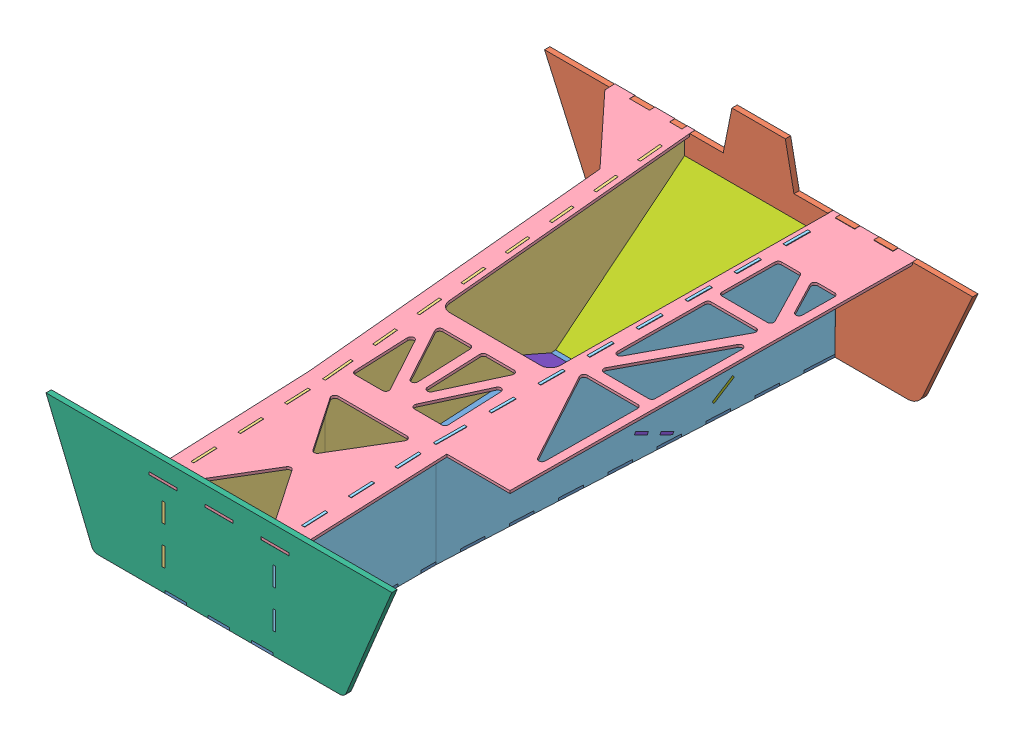
SolidWorks assembly Interior Frame Assembly, configuration Default. Lengths in mm.
Overall size (1628.61 625.54 2073.49).
8 component instances, 8 part files, 25 mates.
Components (placement in the parent):
- Roll Cage Floor Panel-1: Roll Cage Floor Panel [Default] at (605.2647 1125.8511 1278.9155) x (1 0 0) z (0 -1 0) size (582.08 2072.64 10.16)
- Rear Bulkhead-1: Rear Bulkhead [Default] at (-855.024 -1455.0318 1278.9155) size (1628.61 625.54 21.09)
- Side Wall Right-1: Side Wall Right [Default] at (605.2647 1125.8511 1278.9155) x (-1 0 0) z (0 1 0) size (85.33 2072.64 456.87)
- Top Cover-1: Top Cover [Default] at (554.794 1565.6751 1298.1949) x (-0.999997 -0.002279 -0.0001) z (-0.002281 0.999038 0.043792) size (1151.82 2074.69 15.42)
- MirrorSide Wall Right-4: MirrorSide Wall Right [Default] at (605.2647 1125.8511 1278.9155) x (1 0 0) z (0 -1 0) size (85.33 2072.64 456.87)
- Front Bulkhead^Interior Frame Assembly-1: Front Bulkhead^Interior Frame Assembly [Default] at (605.2647 1125.8511 3331.2355) size (1315.72 434.36 20.32) (virtual)
- Part6-1: Part6 [Default] at (605.2647 0 0) x (0 0 -1) z (1 0 0) size (517.46 368.06 582.08)
- Part7^Interior Frame Assembly-1: Part7^Interior Frame Assembly [Default] at (605.2647 0 0) x (0 0 -1) z (1 0 0) size (234.48 107.38 521.41) (virtual)
Mates (geometry in assembly coordinates):
- Coincident1: coincident anti-aligned: plane of Roll Cage Floor Panel-1 through (605.2647 1125.8511 1278.9155) normal (0 1 0); plane of Rear Bulkhead-1 through (-855.024 1125.8511 1273.8355) normal (0 -1 0)
- Coincident2: coincident aligned: plane of Roll Cage Floor Panel-1 through (605.2647 1115.6911 1278.9155) normal (0 0 -1); plane of Rear Bulkhead-1 through (-855.024 -1455.0318 1278.9155) normal (0 0 -1)
- InPlace1: in place: plane of ? through (605.2647 1125.8511 1278.9155) normal (0 1 0); plane of ? through (0 1125.8511 0) normal (0 1 0); moOrthogonalPlaneRef_w of ? through (605.2647 1125.8511 1278.9155) normal (0 1 0); plane of ? through (0 1125.8511 0) normal (0 0 -1); plane of ? through (605.2647 1125.8511 1278.9155) normal (0 1 0); plane of ? through (0 1125.8511 0) normal (1 0 0); plane of ? through (605.2647 1125.8511 1278.9155) normal (0 1 0); unknown of Side Wall Right-1
- Coincident7: coincident aligned: plane of Roll Cage Floor Panel-1; plane of Side Wall Right-1
- Coincident8: coincident aligned: moOrthogonalPlaneRef_w of Roll Cage Floor Panel-1 through (605.2647 1125.8511 1278.9155) normal (0 0 1); plane of Side Wall Right-1 through (605.2647 1125.8511 1278.9155) normal (0 0 1)
- Coincident9: coincident anti-aligned: moOrthogonalPlaneRef_w of Roll Cage Floor Panel-1 through (605.2647 1125.8511 1278.9155) normal (1 0 0); plane of Side Wall Right-1 through (605.2647 1125.8511 1278.9155) normal (-1 0 0)
- Parallel2: parallel aligned: plane of Roll Cage Floor Panel-1 through (605.2647 1125.8511 1278.9155) normal (1 0 0); plane of Wheel Bay Former-1 through (389.3829 1102.9911 2754.6555) normal (1 0 0)
- Coincident24: coincident anti-aligned: line of Side Wall Right-1 through (389.3829 1502.998 2741.9555) axis (0 -1 0); line of Wheel Bay Former-1 through (389.3829 1102.9911 2741.9555) axis (0 1 0)
- Distance2: distance = 12.7 mm: point of Side Wall Right-1; point of Wheel Bay Former-1
- InPlace2: in place: plane of ? through (605.2647 1115.6911 3331.2355) normal (0 0 1); plane of ? through (0 0 3331.2355) normal (0 0 1); plane of ? through (605.2647 1115.6911 3331.2355) normal (0 0 1); plane of ? through (0 0 3331.2355) normal (0 1 0); plane of ? through (605.2647 1115.6911 3331.2355) normal (0 0 1); plane of ? through (0 0 3331.2355) normal (1 0 0); plane of ? through (605.2647 1115.6911 3331.2355) normal (0 0 1); unknown of Front Bulkhead^Interior Frame Assembly-1
- Coincident25: coincident aligned: plane of Roll Cage Floor Panel-1; plane of Front Bulkhead^Interior Frame Assembly-1
- Coincident26: coincident aligned: moOrthogonalPlaneRef_w of Roll Cage Floor Panel-1 through (605.2647 1125.8511 3331.2355) normal (0 1 0); plane of Front Bulkhead^Interior Frame Assembly-1 through (605.2647 1125.8511 3331.2355) normal (0 1 0)
- Coincident27: coincident anti-aligned: moOrthogonalPlaneRef_w of Roll Cage Floor Panel-1 through (605.2647 1125.8511 3331.2355) normal (-1 0 0); plane of Front Bulkhead^Interior Frame Assembly-1 through (605.2647 1125.8511 3331.2355) normal (1 0 0)
- Coincident29: coincident: point of Roll Cage Floor Panel-1; point of Wheel Bay Former-3
- Coincident30: coincident anti-aligned: line of Side Wall Right-1 through (389.3829 1502.998 2741.9555) axis (0 -1 0); line of Wheel Bay Former-3 through (389.3829 1115.6911 2741.9555) axis (0 1 0)
- Coincident31: coincident: point of Roll Cage Floor Panel-1; point of Wheel Bay Former-4
- Coincident32: coincident anti-aligned: line of MirrorSide Wall Right-4 through (821.1465 1502.998 2741.9555) axis (0 -1 0); line of Wheel Bay Former-4 through (821.1465 1115.6911 2741.9555) axis (0 1 0)
- InPlace3: in place: plane of ? through (605.2647 0 0) normal (1 0 0); plane of ? through (605.2647 0 0) normal (0 1 0); plane of ? through (605.2647 0 0) normal (0 0 -1); unknown of ?
- Coincident33: coincident aligned: 
- Coincident34: coincident aligned: plane of Part6-1 through (605.2647 0 0) normal (0 1 0)
- Coincident35: coincident anti-aligned: plane of Part6-1 through (605.2647 0 0) normal (0 0 -1)
- InPlace4: in place: plane of ? through (605.2647 0 0) normal (1 0 0); plane of ? through (605.2647 0 0) normal (0 1 0); plane of ? through (605.2647 0 0) normal (0 0 -1); unknown of ?
- Coincident36: coincident aligned: 
- Coincident37: coincident aligned: plane of Part7^Interior Frame Assembly-1 through (605.2647 0 0) normal (0 1 0)
- Coincident38: coincident anti-aligned: plane of Part7^Interior Frame Assembly-1 through (605.2647 0 0) normal (0 0 -1)
